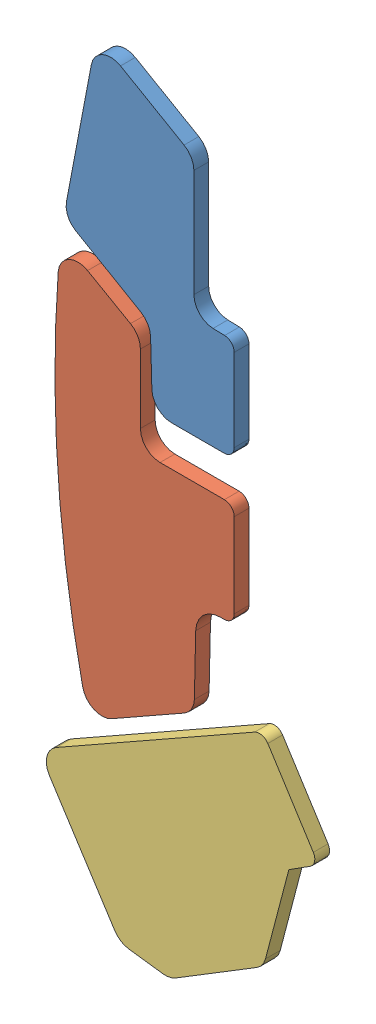
SolidWorks assembly shifterAssem, configuration Default. Lengths in mm.
Overall size (43.7 124.95 2.4).
3 component instances, 3 part files, 7 mates.
Components (placement in the parent):
- topLeftPaddle-1: topLeftPaddle [Default] at (-676.6704 -350.4732 41.1482) size (27.36 46.57 2.4)
- middleLeftPaddle-1: middleLeftPaddle [Default] at (-675.9723 -342.795 41.1482) size (29.18 62.03 2.4)
- clutch-2: clutch [Default] at (-671.3539 -328.6861 41.1482) size (43.7 41.76 2.4)
Mates (geometry in assembly coordinates):
- Coincident22: coincident aligned: plane of topLeftPaddle-1 through (-537.8785 -273.8745 46.8482) normal (0 0 1); plane of middleLeftPaddle-1 through (198.7166 6.8629 46.8482) normal (0 0 1)
- Coincident23: coincident aligned: plane of middleLeftPaddle-1 through (198.7166 6.8629 46.8482) normal (0 0 1); plane of clutch-2 through (-532.5329 -272.7513 46.8482) normal (0 0 1)
- Coincident24: coincident aligned: line of topLeftPaddle-1 through (30.7567 10.934 46.8482) axis (0 1 0); line of middleLeftPaddle-1 through (30.7567 -12.4916 46.8482) axis (0 1 0)
- Parallel10: parallel anti-aligned: line of middleLeftPaddle-1 through (10.8091 -37.2378 46.8482) axis (0.869813 0.493381 0); line of clutch-2 through (34.088 -27.4824 46.8482) axis (-0.869813 -0.493381 0)
- Distance11: distance = 3 mm: line of middleLeftPaddle-1 through (10.8091 -37.2378 46.8482) axis (0.869813 0.493381 0); line of clutch-2 through (34.088 -27.4824 46.8482) axis (-0.869813 -0.493381 0)
- Distance12: distance = 3 mm: point of middleLeftPaddle-1; point of topLeftPaddle-1
- Coincident28: coincident aligned: line of topLeftPaddle-1 through (30.7567 10.934 46.8482) axis (0 1 0); line of middleLeftPaddle-1 through (30.7567 -12.4916 46.8482) axis (0 1 0)
